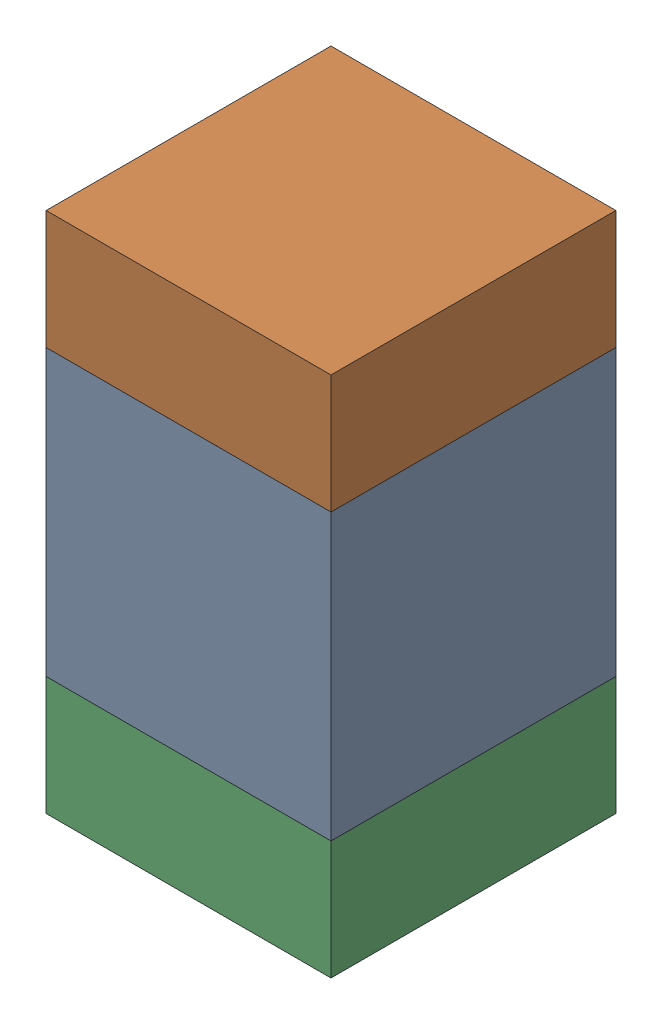
SolidWorks assembly C116_1PCB, configuration Default. Lengths in mm.
Overall size (0.6 1.1 0.6).
6 component instances, 2 part files, 0 mates.
Components (placement in the parent):
- 761606048-1: 761606048 [Default] at (114.7 111.8 0) size (0.6 0.6 0.6)
  - Extruded_9-1: Extruded_9 [Default] at origin size (0.6 0.6 0.6)
- 854785296-1: 854785296 [Default] at (114.7 112.225 0) size (0.6 0.25 0.6)
  - Extruded_10-1: Extruded_10 [Default] at origin size (0.6 0.25 0.6)
- 854785296-2: 854785296 [Default] at (114.7 111.375 0) size (0.6 0.25 0.6)
  - Extruded_10-1: Extruded_10 [Default] at origin size (0.6 0.25 0.6)
